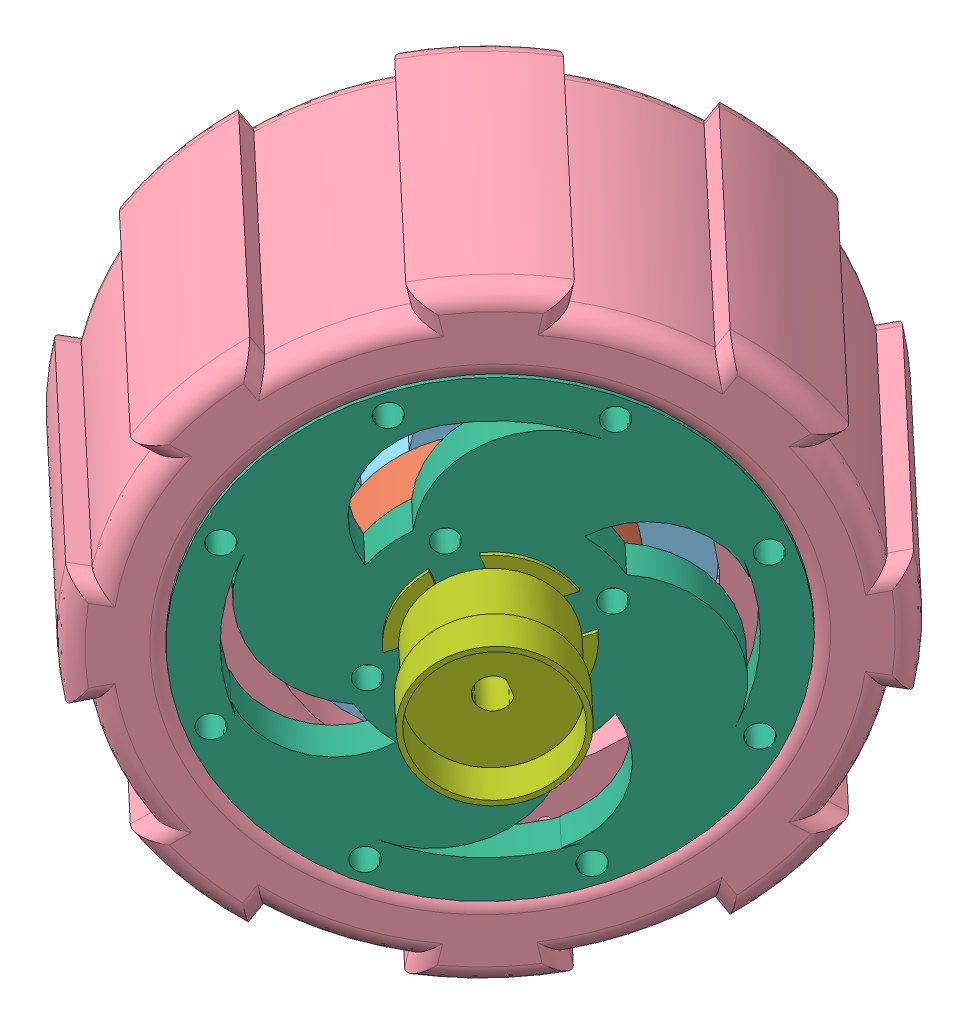
SolidWorks assembly Wheel_Assembly, configuration Default. Lengths in mm.
Overall size (212.46 224.32 217.39).
7 component instances, 7 part files, 18 mates.
Components (placement in the parent):
- Outside Ring_2-1: Outside Ring_2 [Default] at (-144.0965 551 227.16) x (-0.648172 -0.343454 0.679641) z (0.727193 -0.014323 0.686284) size (120 120 10)
- Motor_Connector_Ring-1: Motor_Connector_Ring [Default] at (-100.4649 550.1406 268.337) x (0.648172 0.343454 -0.679641) z (0.727193 -0.014323 0.686284) size (58 58 15)
- Motor_Connector_Ring_2-1: Motor_Connector_Ring_2 [Default] at (-133.1886 550.7852 237.4542) x (0.648172 0.343454 -0.679641) z (0.727193 -0.014323 0.686284) size (58 58 15)
- Tire-2: Tire [Default] at (-151.3684 551.1432 220.2971) x (-0.390438 -0.830933 0.39637) z (-0.564578 0.556189 0.60984) size (160.88 80.88 160.88)
- Inner Ring-1: Inner Ring [Default] at (-111.3728 550.3555 258.0427) x (0.648172 0.343454 -0.679641) z (0.727193 -0.014323 0.686284) size (120 120 30)
- Outside Ring_1-1: Outside Ring_1 [Default] at (-93.193 549.9974 275.1998) x (0.648172 0.343454 -0.679641) z (0.727193 -0.014323 0.686284) size (120 120 10)
- Wheel_Brushing_Connector-1: Wheel_Brushing_Connector [Default] at (-80.6453 549.7503 287.0417) x (-0.225973 0.93906 0.259041) z (-0.648172 -0.343454 0.679641) size (38.73 107.25 38.73)
Mates (geometry in assembly coordinates):
- Coincident38: coincident anti-aligned: plane of Motor_Connector_Ring-1 through (-100.4649 550.1406 268.337) normal (0.727193 -0.014323 0.686284); plane of Outside Ring_1-1 through (-100.4649 550.1406 268.337) normal (-0.727193 0.014323 -0.686284)
- Coincident39: coincident aligned: plane of Motor_Connector_Ring-1 through (-117.8545 546.9209 264.8391) normal (0.648172 0.343454 -0.679641); plane of Outside Ring_1-1 through (-106.9466 546.7061 275.1334) normal (0.648172 0.343454 -0.679641)
- Coincident40: coincident aligned: plane of Motor_Connector_Ring-1 through (-113.6325 559.7461 260.6331) normal (0.225973 -0.93906 -0.259041); plane of Outside Ring_1-1 through (-102.7246 559.5312 270.9274) normal (0.225973 -0.93906 -0.259041)
- Coincident42: coincident anti-aligned: plane of Motor_Connector_Ring-1 through (-111.3728 550.3555 258.0427) normal (-0.727193 0.014323 -0.686284); plane of Inner Ring-1 through (-111.3728 550.3555 258.0427) normal (0.727193 -0.014323 0.686284)
- Coincident43: coincident aligned: plane of Motor_Connector_Ring-1 through (-109.1131 540.9649 255.4523) normal (-0.225973 0.93906 0.259041); plane of Inner Ring-1 through (-130.9289 541.3946 234.8638) normal (-0.225973 0.93906 0.259041)
- Coincident44: coincident aligned: plane of Motor_Connector_Ring-1 through (-104.8911 553.79 251.2463) normal (-0.648172 -0.343454 0.679641); plane of Inner Ring-1 through (-126.7069 554.2197 230.6578) normal (-0.648172 -0.343454 0.679641)
- Coincident45: coincident anti-aligned: plane of Motor_Connector_Ring_2-1 through (-133.1886 550.7852 237.4542) normal (0.727193 -0.014323 0.686284); plane of Inner Ring-1 through (-133.1886 550.7852 237.4542) normal (-0.727193 0.014323 -0.686284)
- Coincident46: coincident aligned: plane of Motor_Connector_Ring_2-1 through (-141.8368 541.6094 224.5696) normal (-0.225973 0.93906 0.259041); plane of Inner Ring-1 through (-130.9289 541.3946 234.8638) normal (-0.225973 0.93906 0.259041)
- Coincident47: coincident aligned: plane of Motor_Connector_Ring_2-1 through (-137.6148 554.4345 220.3636) normal (-0.648172 -0.343454 0.679641); plane of Inner Ring-1 through (-126.7069 554.2197 230.6578) normal (-0.648172 -0.343454 0.679641)
- Coincident48: coincident aligned: plane of Outside Ring_2-1 through (-144.8867 554.5778 213.5007) normal (-0.648172 -0.343454 0.679641); plane of Motor_Connector_Ring_2-1 through (-137.6148 554.4345 220.3636) normal (-0.648172 -0.343454 0.679641)
- Coincident49: coincident anti-aligned: plane of Outside Ring_2-1 through (-144.0965 551 227.16) normal (0.727193 -0.014323 0.686284); plane of Motor_Connector_Ring_2-1 through (-144.0965 551 227.16) normal (-0.727193 0.014323 -0.686284)
- Coincident50: coincident aligned: plane of Outside Ring_2-1 through (-153.6281 560.5338 222.8875) normal (0.225973 -0.93906 -0.259041); plane of Motor_Connector_Ring_2-1 through (-146.3562 560.3906 229.7504) normal (0.225973 -0.93906 -0.259041)
- Parallel5: parallel anti-aligned: plane of Outside Ring_2-1 through (-144.0965 551 227.16) normal (0.727193 -0.014323 0.686284); plane of Tire-2 through (-140.4605 550.9284 230.5914) normal (-0.727193 0.014323 -0.686284)
- Coincident53: coincident aligned: plane of Outside Ring_2-1 through (-151.3684 551.1432 220.2971) normal (-0.727193 0.014323 -0.686284); plane of Tire-2 through (-151.3684 551.1432 220.2971) normal (-0.727193 0.014323 -0.686284)
- Concentric21: concentric anti-aligned: cylinder of Outside Ring_2-1 through (-151.3684 551.1432 220.2971) axis (0.727193 -0.014323 0.686284) radius 60; cylinder of Tire-2 through (-144.0965 551 227.16) axis (-0.727193 0.014323 -0.686284) radius 60
- Coincident55: coincident anti-aligned: plane of Outside Ring_1-1 through (-103.7058 548.4234 271.7352) normal (-0.648172 -0.343454 0.679641); plane of Wheel_Brushing_Connector-1 through (-37.5312 547.12 334.187) normal (0.648172 0.343454 -0.679641)
- Coincident56: coincident anti-aligned: plane of Motor_Connector_Ring-1 through (-109.1131 540.9649 255.4523) normal (-0.225973 0.93906 0.259041); plane of Wheel_Brushing_Connector-1 through (-32.0306 539.4467 328.1984) normal (0.225973 -0.93906 -0.259041)
- Coincident60: coincident aligned: plane of Outside Ring_2-1 through (-151.3684 551.1432 220.2971) normal (-0.727193 0.014323 -0.686284); plane of Wheel_Brushing_Connector-1 through (-151.3684 551.1432 220.2971) normal (-0.727193 0.014323 -0.686284)
